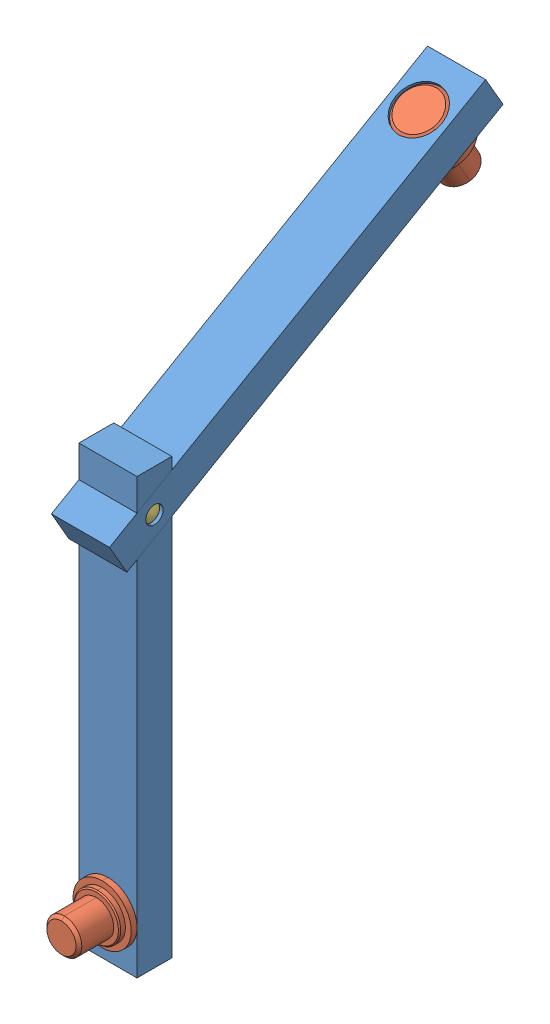
SolidWorks assembly 110303047-62, configuration 預設. Lengths in mm.
Overall size (12.6 103.91 73.96).
7 component instances, 4 part files, 11 mates.
Components (placement in the parent):
- long_link_section-1: long_link_section [預設] at (83.2925 19.5219 -74.035) x (0 1 0) z (1 0 0) size (74.74 6 10)
- long_link_section-2: long_link_section [預設] at (83.2925 19.5219 -74.035) x (0 -0.5 0.866025) z (-1 0 0) size (74.74 6 10)
- revolute_joint-1: revolute_joint [預設] at (83.2925 112.1866 -20.535) x (-0.308797 -0.475564 0.823701) z (0.951128 -0.154398 0.267426) size (10 14 10)
- MSCSS3-10-1: MSCSS3-10 [預設] at (83.2925 79.5663 29.965) x (-1 0 0) z (0 -0.944487 -0.328548) size (10 3 3)
- MSSFS3-4-1: MSSFS3-4 [預設] at (83.2925 112.3386 -26.7982) x (0 -0.5 0.866025) z (0.812856 0.504429 0.291232) size (4 3 3)
- MSSFS3-4-2: MSSFS3-4 [預設] at (83.2925 14.0219 29.965) x (0 1 0) z (0 0 1) size (4 3 3)
- revolute_joint-3: revolute_joint [預設] at (83.2925 19.5219 26.965) x (1 0 0) z (0 -1 0) size (10 14 10)
Mates (geometry in assembly coordinates):
- 同軸心1: concentric anti-aligned: cylinder of long_link_section-2 through (83.2925 75.7716 30.5376) axis (0 0.866025 0.5) radius 4; cylinder of revolute_joint-1 through (83.2925 80.9678 33.5376) axis (0 -0.866025 -0.5) radius 4
- 重合/共線/共點1: coincident aligned: plane of long_link_section-2 through (78.2925 84.7178 27.0424) normal (0 0.866025 0.5); plane of revolute_joint-1 through (84.5277 82.8701 30.2428) normal (0 0.866025 0.5)
- 輪廓中心2: profile center anti-aligned: plane of long_link_section-1 through (88.2925 12.0219 26.965) normal (0 -1 0); circle of MSSFS3-4-2
- 輪廓中心3: profile center anti-aligned: plane of long_link_section-2 through (78.2925 79.5216 24.0424) normal (0 0.5 -0.866025); circle of MSSFS3-4-1
- 重合/共線/共點3: coincident anti-aligned: plane of long_link_section-1 through (83.2925 19.5219 -74.035) normal (1 0 0); plane of long_link_section-2 through (83.2925 -11.6969 -19.9624) normal (-1 0 0)
- 同軸心5: concentric aligned: cylinder of long_link_section-1 through (83.2925 19.5219 26.965) axis (0 0 1) radius 4; cylinder of revolute_joint-3 through (83.2925 19.5219 26.965) axis (0 0 1) radius 4
- 重合/共線/共點7: coincident anti-aligned: plane of long_link_section-1 through (88.2925 12.0219 32.965) normal (0 0 1); plane of revolute_joint-3 through (78.2925 19.5219 32.965) normal (0 0 -1)
- 同軸心6: concentric anti-aligned: cylinder of long_link_section-1 through (78.2925 79.5663 29.965) axis (1 0 0) radius 1.5; cylinder of MSCSS3-10-1 through (78.2925 79.5663 29.965) axis (-1 0 0) radius 1.5
- 重合/共線/共點8: coincident aligned: plane of long_link_section-1 through (78.2925 19.5219 -74.035) normal (-1 0 0); plane of MSCSS3-10-1 through (78.2925 79.9711 28.8013) normal (-1 0 0)
- 重合/共線/共點9: coincident anti-aligned: plane of long_link_section-1 through (88.2925 77.8343 26.965) normal (0 0.866025 0.5); plane of long_link_section-2 through (78.2925 110.7405 -30.0302) normal (0 -0.866025 -0.5)
- 重合/共線/共點12: coincident anti-aligned: plane of long_link_section-1 through (88.2925 12.0219 32.965) normal (0 0 1); plane of long_link_section-2 through (78.2925 81.2984 32.965) normal (0 0 -1)
